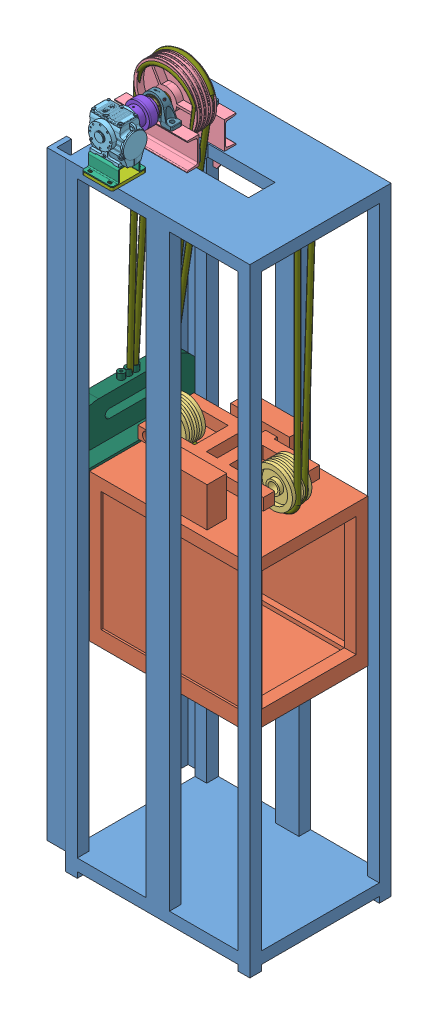
SolidWorks assembly ELEVATOR, configuration Default. Lengths in mm.
Overall size (1040 3530.57 749).
43 component instances, 16 part files, 17 mates.
Components (placement in the parent):
- main-1: main [Default] at (1.7459 -411.7267 0.2518) size (1035 3150 720)
- Part1-1: Part1 [Default] at (3.7459 577.5056 0.2518) x (0 0 1) z (-1 0 0) size (600 950 820)
- pully-1: pully [Default] at (-267.5789 1467.5056 -3.6011) x (-0.862623 -0.505847 0) z (0 0 -1) size (199 199 99)
- pully-2: pully [Default] at (275.0706 1467.5056 -3.6011) x (-0.905494 -0.424358 0) z (0 0 -1) size (199 199 99)
- Main_Assembly-1: Main_Assembly [Default] at (-278.3755 2708.2733 -9.7482) x (0 0 1) z (-1 0 0) size (544 500.57 370)
  - ELEVATOR DRIVE SYSTEM-1: ELEVATOR DRIVE SYSTEM [Default] at (0 197.2 0) x (1 0 0) z (0 1 0) size (249.8 370 480.2)
  - SA_57_20220810_125725__p54_1nvjke1Qz8k1_Z8fg-1: SA_57_20220810_125725__p54_1nvjke1Qz8k1_Z8fg [Default] at (311.5 197.2 0) x (0 0 -1) z (0 1 0) size (188 154 188.5)
  - Motor_Base_Plate-1: Motor_Base_Plate [Default] at (311.5 15 0) size (175 69 154)
  - Base_Plate-1: Base_Plate [Default] at (311.5 0 0) size (175 15 154)
  - coupling-2: coupling [Default] at (184 197.2 0) size (108 125 125)
  - Main_Shaft-1: Main_Shaft [Default] at (0 197.2 0) x (1 0 0) z (0 0.005978 0.999982) size (327 60 60)
  - Motor_shaft-1: Motor_shaft [Default] at (285.75 197.2 0) size (201.5 30 30)
  - SKF_UCP_210-1: SKF_UCP_210 [Default] at (-94.9 197.2 0) size (60.6 240.57 206.52)
    - SKF_UCP_210_3-1: SKF_UCP_210_3 [Default] at (0 63.3156 20.5725) x (1 0 0) z (0 0 -1) size (12.7 12.7 12.7)
    - SKF_UCP_210_3-2: SKF_UCP_210_3 [Default] at (0 45.8156 33.287) x (1 0 0) z (0 0 -1) size (12.7 12.7 12.7)
    - SKF_UCP_210_3-3: SKF_UCP_210_3 [Default] at (0 24.1844 33.287) x (1 0 0) z (0 0 -1) size (12.7 12.7 12.7)
    - SKF_UCP_210_3-4: SKF_UCP_210_3 [Default] at (0 6.6844 20.5725) x (1 0 0) z (0 0 -1) size (12.7 12.7 12.7)
    - SKF_UCP_210_3-5: SKF_UCP_210_3 [Default] x (1 0 0) z (0 0 -1) size (12.7 12.7 12.7)
    - SKF_UCP_210_3-6: SKF_UCP_210_3 [Default] at (0 6.6844 -20.5725) x (1 0 0) z (0 0 -1) size (12.7 12.7 12.7)
    - SKF_UCP_210_3-7: SKF_UCP_210_3 [Default] at (0 24.1844 -33.287) x (1 0 0) z (0 0 -1) size (12.7 12.7 12.7)
    - SKF_UCP_210_3-8: SKF_UCP_210_3 [Default] at (0 45.8156 -33.287) x (1 0 0) z (0 0 -1) size (12.7 12.7 12.7)
    - SKF_UCP_210_3-9: SKF_UCP_210_3 [Default] at (0 63.3156 -20.5725) x (1 0 0) z (0 0 -1) size (12.7 12.7 12.7)
    - SKF_UCP_210_3-10: SKF_UCP_210_3 [Default] at (0 70 0) x (1 0 0) z (0 0 -1) size (12.7 12.7 12.7)
    - SKF_UCP_210_14-1: SKF_UCP_210_14 [Default] x (-1 0 0) z (0 0 -1) size (51.6 90 90)
    - SKF_UCP_210_16-1: SKF_UCP_210_16 [Default] at (-3 41.5779 41.5779) x (1 0 0) z (0 -0.707107 0.707107) size (15.16 17.49 15.49)
    - SKF_UCP_210_18-1: SKF_UCP_210_18 [Default] x (0 0 1) z (-1 0 0) size (206.52 240.57 56)
  - SKF_UCP_210-2: SKF_UCP_210 [Default] at (94.9 197.2 0) x (-1 0 0) z (0 0 -1) size (60.6 240.57 206.52)
    - SKF_UCP_210_3-1: SKF_UCP_210_3 [Default] at (0 63.3156 20.5725) x (1 0 0) z (0 0 -1) size (12.7 12.7 12.7)
    - SKF_UCP_210_3-2: SKF_UCP_210_3 [Default] at (0 45.8156 33.287) x (1 0 0) z (0 0 -1) size (12.7 12.7 12.7)
    - SKF_UCP_210_3-3: SKF_UCP_210_3 [Default] at (0 24.1844 33.287) x (1 0 0) z (0 0 -1) size (12.7 12.7 12.7)
    - SKF_UCP_210_3-4: SKF_UCP_210_3 [Default] at (0 6.6844 20.5725) x (1 0 0) z (0 0 -1) size (12.7 12.7 12.7)
    - SKF_UCP_210_3-5: SKF_UCP_210_3 [Default] x (1 0 0) z (0 0 -1) size (12.7 12.7 12.7)
    - SKF_UCP_210_3-6: SKF_UCP_210_3 [Default] at (0 6.6844 -20.5725) x (1 0 0) z (0 0 -1) size (12.7 12.7 12.7)
    - SKF_UCP_210_3-7: SKF_UCP_210_3 [Default] at (0 24.1844 -33.287) x (1 0 0) z (0 0 -1) size (12.7 12.7 12.7)
    - SKF_UCP_210_3-8: SKF_UCP_210_3 [Default] at (0 45.8156 -33.287) x (1 0 0) z (0 0 -1) size (12.7 12.7 12.7)
    - SKF_UCP_210_3-9: SKF_UCP_210_3 [Default] at (0 63.3156 -20.5725) x (1 0 0) z (0 0 -1) size (12.7 12.7 12.7)
    - SKF_UCP_210_3-10: SKF_UCP_210_3 [Default] at (0 70 0) x (1 0 0) z (0 0 -1) size (12.7 12.7 12.7)
    - SKF_UCP_210_14-1: SKF_UCP_210_14 [Default] x (-1 0 0) z (0 0 -1) size (51.6 90 90)
    - SKF_UCP_210_16-1: SKF_UCP_210_16 [Default] at (-3 41.5779 41.5779) x (1 0 0) z (0 -0.707107 0.707107) size (15.16 17.49 15.49)
    - SKF_UCP_210_18-1: SKF_UCP_210_18 [Default] x (0 0 1) z (-1 0 0) size (206.52 240.57 56)
- load-1: load [Default] at (-468.2541 1077.0476 4.7908) x (0 0 1) z (-1 0 0) size (660.06 854.62 100.05)
- new_cre-1: new_cre [Default] at (-468.2764 1077.0578 5.5982) x (0 0 1) z (-1 0.000057 0) size (58.15 1712.15 894.92)
- new_cre-2: new_cre [Default] at (-462.0651 1056.6716 21.6546) x (-0.014579 -0.029126 0.999469) z (-0.999883 -0.004224 -0.014708) size (58.15 1712.15 894.92)
Mates (geometry in assembly coordinates):
- Distance8: distance = 2 mm anti-aligned: plane of Part1-1 through (-406.2541 657.5056 0.2518) normal (-1 0 0); plane of main-1 through (-408.2541 2648.2733 360.2518) normal (1 0 0)
- Concentric3: concentric anti-aligned: circle of Part1-1; circle of pully-1
- Coincident48: coincident anti-aligned: line of Main_Assembly-1/Base_Plate-1 through (-211.3755 2708.2733 214.2518) axis (-1 0 0)
- Distance9: distance = 40 mm anti-aligned: plane of pully-1 through (-267.5789 1467.5056 45.8989) normal (0 0 1); plane of Part1-1 through (-316.2541 1497.5056 85.8989) normal (0 0 -1)
- Distance10: distance = 40 mm anti-aligned: plane of pully-2 through (275.0706 1467.5056 45.8989) normal (0 0 1); plane of Part1-1 through (-316.2541 1497.5056 85.8989) normal (0 0 -1)
- Concentric4: concentric anti-aligned: circle of Part1-1; circle of pully-2
- Coincident34: coincident anti-aligned: plane of main-1 through (-468.2541 2648.2733 300.2518) normal (0 0 -1); plane of Part1-1 through (3.7459 657.5056 300.2518) normal (0 0 1)
- Coincident49: coincident anti-aligned: plane of main-1 through (1.7459 2708.2733 0.2518) normal (0 1 0); plane of Main_Assembly-1/Base_Plate-1 through (-278.3755 2708.2733 301.7518) normal (0 -1 0)
- Coincident50: coincident anti-aligned: plane of main-1 through (-468.2541 -351.7267 -359.7482) normal (-1 0 0); plane of load-1 through (-468.2541 1077.0476 4.7908) normal (1 0 0)
- Coincident51: coincident anti-aligned: plane of main-1 through (-433.9377 -515.1976 334.7908) normal (0 0 -1); plane of load-1 through (-538.2541 1277.0476 334.7908) normal (0 0 1)
- Linear/Linear Coupler1: linear coupler = 1 : 1 mm: plane of Part1-1 through (3.7459 1327.5056 0.2518) normal (0 1 0); plane of load-1 through (207.4167 1561.666 -181.9413) normal (0 1 0)
- LimitDistance1: limit distance = 1320.7677 mm anti-aligned: plane of Part1-1 through (3.7459 1327.5056 0.2518) normal (0 1 0); plane of main-1 through (1.7459 2648.2733 0.2518) normal (0 -1 0)
- Concentric9: concentric aligned: circle of pully-1; circle of new_cre-1
- Concentric10: concentric anti-aligned: circle of Main_Assembly-1/ELEVATOR DRIVE SYSTEM-1; circle of new_cre-1
- Coincident52: coincident anti-aligned: line of Main_Assembly-1/Base_Plate-1 through (-201.3755 2708.2733 379.2518) axis (0 0 -1)
- Parallel8: parallel anti-aligned: plane of main-1 through (366.7459 2578.2733 12.2518) normal (0 -1 0); plane of new_cre-2 through (366.7459 2562.7142 12.2518) normal (0 1 0)
- Concentric14: concentric aligned: circle of main-1; circle of new_cre-2
